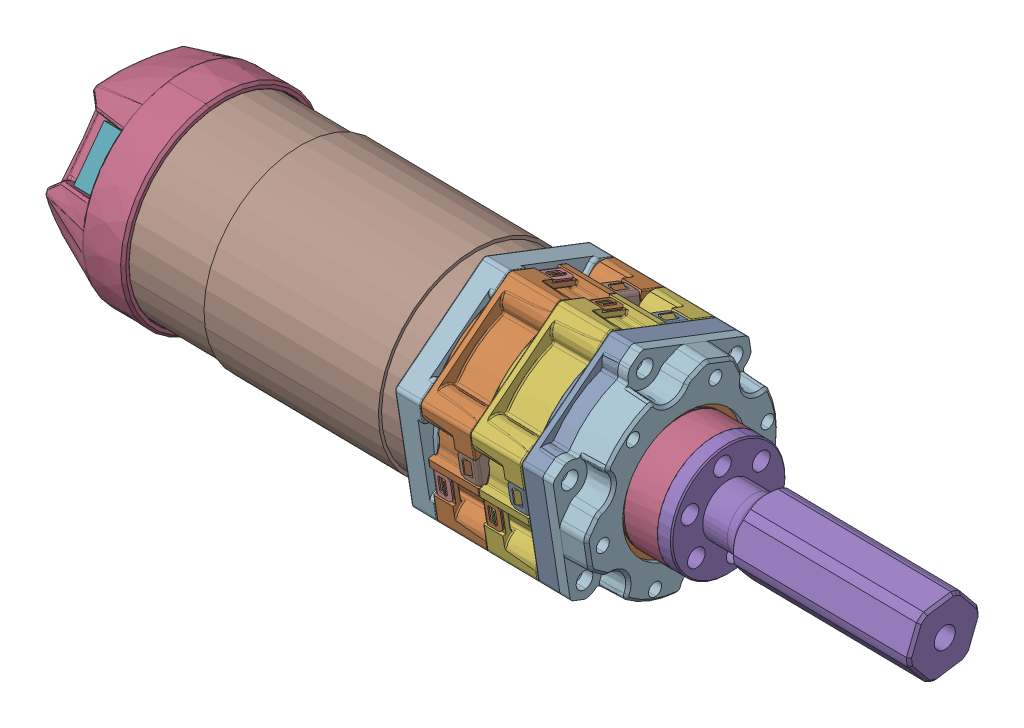
SolidWorks assembly MotorREV_2Etapas, configuration Default. Lengths in mm.
Overall size (161 51.15 54.4).
6 component instances, 6 part files, 11 mates.
Components (placement in the parent):
- REV-41-1291_NoGearbox-1: REV-41-1291_NoGearbox [Default] x (0.008706 0.160776 -0.986953) z (0.004678 0.986973 0.16082) size (38.76 83.12 38.76)
- REV-41-1602_Cartridge4-1-1: REV-41-1602_Cartridge4-1 [Default] at (52.1952 28.9124 -3.3004) x (-0.004699 -0.987362 -0.158409) z (-0.999951 0.006017 -0.007841) size (43.62 38.42 17.88)
- REV-41-1603_Cartridge5-1-1: REV-41-1603_Cartridge5-1 [Default] at (61.9447 28.8538 -3.2239) x (-0.004699 -0.987362 -0.158409) z (-0.999951 0.006017 -0.007841) size (43.62 38.42 17.88)
- REV-41-1607_550MotorPlate-1: REV-41-1607_550MotorPlate [Default] at (42.3207 28.9719 -3.3778) x (-0.004699 -0.987362 -0.158409) z (-0.008695 -0.158364 0.987342) size (43.57 5 38.01)
- REV-41-1615_FemaleHex-1: REV-41-1615_FemaleHex [Default] at (78.1939 28.756 -3.0965) x (-0.00518 0.356534 0.934268) z (-0.999951 0.006017 -0.007841) size (43.57 38 18.25)
- REV-41-1620_HexAdapter-1: REV-41-1620_HexAdapter [Default] at (83.6936 28.7229 -3.0534) x (0.008417 0.934263 -0.356485) z (-0.999951 0.006017 -0.007841) size (22 22 46.85)
Mates (geometry in assembly coordinates):
- Coincidente6: coincident: point of REV-41-1291_NoGearbox-1
- Coincidente7: coincident aligned: circle of REV-41-1291_NoGearbox-1; circle of REV-41-1607_550MotorPlate-1
- Concéntrica3: coincident anti-aligned: circle of REV-41-1602_Cartridge4-1-1; circle of REV-41-1603_Cartridge5-1-1
- Coincidente10: coincident aligned: line of REV-41-1602_Cartridge4-1-1 through (57.0529 20.6975 -23.3124) axis (-0.999951 0.006017 -0.007841); line of REV-41-1603_Cartridge5-1-1 through (66.8024 20.6389 -23.2359) axis (-0.999951 0.006017 -0.007841)
- Concéntrica4: concentric aligned: circle of REV-41-1602_Cartridge4-1-1; circle of REV-41-1607_550MotorPlate-1
- Coincidente11: coincident anti-aligned: line of REV-41-1602_Cartridge4-1-1 through (57.159 42.1537 -20.3764) axis (-0.999951 0.006017 -0.007841); line of REV-41-1607_550MotorPlate-1 through (42.7847 42.2402 -20.4891) axis (0.999951 -0.006017 0.007841)
- Coincidente12: coincident anti-aligned: plane of REV-41-1602_Cartridge4-1-1 through (47.3204 28.9418 -3.3386) normal (-0.999951 0.006017 -0.007841); plane of REV-41-1607_550MotorPlate-1 through (47.3204 28.9418 -3.3386) normal (0.999951 -0.006017 0.007841)
- Coincidente13: coincident: circle of REV-41-1603_Cartridge5-1-1; circle of REV-41-1615_FemaleHex-1
- Coincidente14: coincident anti-aligned: line of REV-41-1603_Cartridge5-1-1 through (66.4804 15.5553 13.9266) axis (-0.999951 0.006017 -0.007841); line of REV-41-1615_FemaleHex-1 through (66.9804 15.5523 13.9305) axis (0.999951 -0.006017 0.007841)
- Concéntrica5: concentric: circle of REV-41-1615_FemaleHex-1; circle of REV-41-1620_HexAdapter-1
- Coincidente15: coincident anti-aligned: circle of REV-41-1615_FemaleHex-1; circle of REV-41-1620_HexAdapter-1
